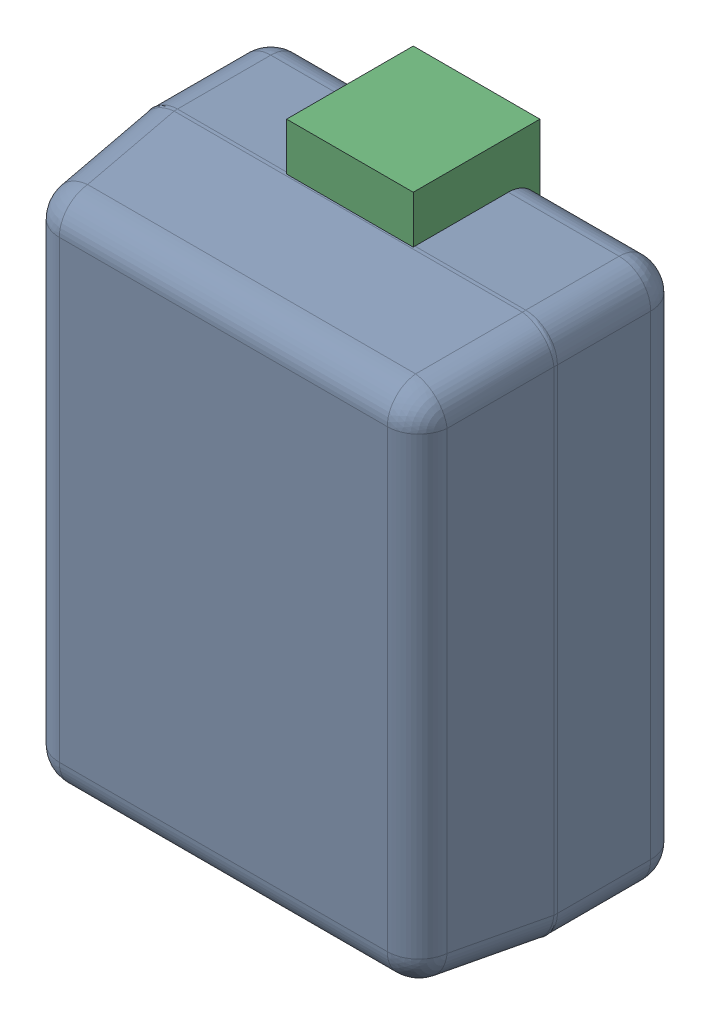
SolidWorks assembly D82.step, configuration Default. Lengths in mm.
Overall size (0.66 1 0.4).
5 component instances, 2 part files, 0 mates.
Components (placement in the parent):
- 6297722768.step-1: 6297722768.step [Default] at (22.987 -1.9844 0) x (0 1 0) z (0 0 1) size (1 0.66 0.4)
  - Body (8).step-1: Body (8).step [Default] at (-0.425 -0.325 0) size (0.85 0.66 0.4)
    - Open CASCADE STEP translator 6.8 15.1.1.step-1: Open CASCADE STEP translator 6.8 15.1.1.step [Default] at origin size (0.85 0.66 0.4)
  - lead.step-1: lead.step [Default] at (-0.5 -0.1 0) size (0.19 0.2 0.2)
  - lead.step-2: lead.step [Default] at (0.5 0.1 0) x (-1 0 0) z (0 0 1) size (0.19 0.2 0.2)
